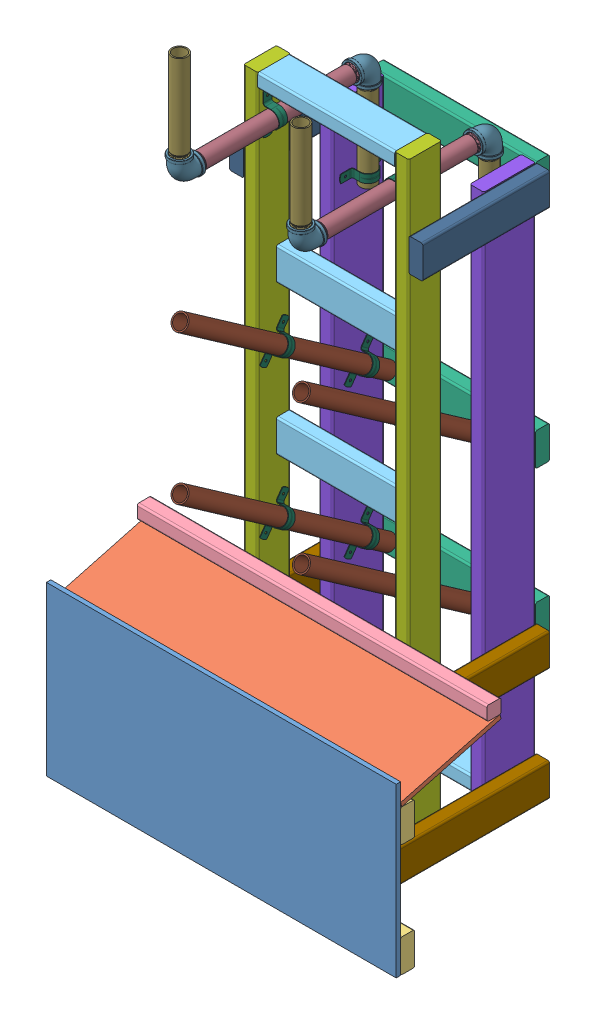
SolidWorks assembly TE-25300, configuration Full Assembly. Lengths in mm.
Overall size (946.66 1825.49 664.9).
50 component instances, 16 part files, 102 mates.
Components (placement in the parent):
- TE Goal Layout-1: TE Goal Layout [Default] at origin size (946.66 1825.49 664.9) (hidden)
- TE-25301-1: TE-25301 [Default] at (0 0 831.7368) size (946.66 454.03 11.91)
- TE-25302-1: TE-25302 [Default] at (0 582.9571 156.2029) x (1 0 0) z (0 0.965926 0.258819) size (946.66 278.4 11.91)
- TE-25303-1: TE-25303 [Default] at (473.3294 0 0) x (0 0 -1) z (1 0 0) size (38.1 88.9 946.66)
- TE-25303-2: TE-25303 [Default] at (473.3294 304.7381 0) x (0 0 -1) z (1 0 0) size (38.1 88.9 946.66)
- TE-25304-1: TE-25304 [Default] at (473.3294 0 0) x (0 0 -1) z (1 0 0) size (38.1 38.1 946.66)
- TE-25305-1: TE-25305 [Default] at (185.3882 0 0) x (0 0 1) z (-1 0 0) size (88.9 38.1 370.78)
- TE-25305-2: TE-25305 [Default] at (185.3882 0 -254) x (0 0 1) z (-1 0 0) size (88.9 38.1 370.78)
- TE-25305-3: TE-25305 [Default] at (185.3882 270.0939 497.0322) x (0 1 0) z (-1 0 0) size (88.9 38.1 370.78)
- TE-25305-4: TE-25305 [Default] at (185.3882 673.1937 497.0322) x (0 1 0) z (-1 0 0) size (88.9 38.1 370.78)
- TE-25305-5: TE-25305 [Default] at (185.3882 1612.9 0) x (0 0 1) z (-1 0 0) size (88.9 38.1 370.78)
- TE-25306-1: TE-25306 [Default] at (223.4882 0 0) x (0 0 -1) z (1 0 0) size (38.1 88.9 446.98)
- TE-25306-2: TE-25306 [Default] at (223.4882 403.0998 0) x (0 0 -1) z (1 0 0) size (38.1 88.9 446.98)
- TE-25306-3: TE-25306 [Default] at (223.4882 1032.6496 0) x (0 0 -1) z (1 0 0) size (38.1 88.9 446.98)
- TE-25321-1: TE-25321 [Default] at (223.4882 0 0) x (0 0 -1) z (1 0 0) size (88.9 1651 38.1)
- TE-25322-1: TE-25322 [Default] at (223.4882 0 0) x (0 0 -1) z (1 0 0) size (139.7 1473.2 38.1)
- TE-25324-2: TE-25324 [Default] at (261.5883 0 0) x (0 0 -1) z (1 0 0) size (576.8 88.9 38.1)
- TE-25324-3: TE-25324 [Default] at (261.5883 304.7381 0) x (0 0 -1) z (1 0 0) size (576.8 88.9 38.1)
- TE-25323-1: TE-25323 [Default] at (0 0 547.8322) size (38.1 88.9 342.9)
- TE-25312-1: TE-25312 [Default] at (0 625.9586 893.9616) x (1 0 0) z (0 0.573576 0.819152) size (42.16 42.16 686.36)
- TE-25312-2: TE-25312 [Default] at (0 1029.0584 893.9616) x (1 0 0) z (0 0.573576 0.819152) size (42.16 42.16 686.36)
- TE-25313-1: TE-25313 [9157K765] at (164.3062 1698.4878 780.7502) x (0 -1 0) z (0 0 1) size (254.3 44.49 44.03)
- TE-25314-1: TE-25314 [4457K117] at (164.3062 1545.0718 525.7342) size (44.11 43.64 458.81)
- TE-25315-1: TE-25315 [44605K117] at (164.3062 1545.0718 780.7502) x (0 0 1) z (-1 0 0) size (71.9 71.9 54.61)
- TE-25313-2: TE-25313 [9157K765] at (164.3062 1391.6558 270.7182) x (0 1 0) z (-0.546944 0 0.837169) size (254.3 44.49 44.03)
- TE-25315-2: TE-25315 [44605K117] at (164.3062 1545.0718 270.7182) x (0 1 0) z (1 0 0) size (71.9 71.9 54.61)
- TE-25316-1: TE-25316 [9439T23] at (163.9506 1290.0558 270.7182) x (0 0 -1) z (0 1 0) size (111.12 44.78 22.23)
- TE-25316-2: TE-25316 [9439T23] at (163.9506 1545.0718 522.4322) x (0 1 0) z (0 0 1) size (111.12 44.78 22.23)
- TE-25316-3: TE-25316 [9439T23] at (163.9506 839.6426 274.7822) x (0 0.819152 -0.573576) z (0 0.573576 0.819152) size (111.12 44.78 22.23)
- TE-25316-4: TE-25316 [9439T23] at (163.9506 999.7101 503.3822) x (0 0.819152 -0.573576) z (0 0.573576 0.819152) size (111.12 44.78 22.23)
- TE-25316-5: TE-25316 [9439T23] at (163.9506 436.5429 274.7822) x (0 0.819152 -0.573576) z (0 0.573576 0.819152) size (111.12 44.78 22.23)
- TE-25316-6: TE-25316 [9439T23] at (163.9506 596.6103 503.3822) x (0 0.819152 -0.573576) z (0 0.573576 0.819152) size (111.12 44.78 22.23)
- TE-25321-2: TE-25321 [Default] at (-185.3882 0 0) x (0 0 -1) z (1 0 0) size (88.9 1651 38.1)
- TE-25314-2: TE-25314 [4457K117] at (-164.3062 1544.7026 525.7342) x (-1 0 0) z (0 0 1) size (44.11 43.64 458.81)
- TE-25324-4: TE-25324 [Default] at (-223.4882 0 0) x (0 0 -1) z (1 0 0) size (576.8 88.9 38.1)
- TE-25323-2: TE-25323 [Default] at (0 0 204.9322) x (-1 0 0) z (0 0 -1) size (38.1 88.9 342.9)
- TE-25322-2: TE-25322 [Default] at (-185.3882 0 0) x (0 0 -1) z (1 0 0) size (139.7 1473.2 38.1)
- TE-25312-3: TE-25312 [Default] at (0 635.3809 331.7318) x (-1 0 0) z (0 -0.573576 -0.819152) size (42.16 42.16 686.36)
- TE-25313-3: TE-25313 [9157K765] at (-164.0591 1698.4878 780.7502) x (0 -1 0) z (0 0 1) size (254.3 44.49 44.03)
- TE-25324-5: TE-25324 [Default] at (-223.4882 304.7381 0) x (0 0 -1) z (1 0 0) size (576.8 88.9 38.1)
- TE-25312-4: TE-25312 [Default] at (0 232.2811 331.7318) x (-1 0 0) z (0 -0.573576 -0.819152) size (42.16 42.16 686.36)
- TE-25316-7: TE-25316 [9439T23] at (-163.9506 999.7101 503.3822) x (0 0.819152 -0.573576) z (0 -0.573576 -0.819152) size (111.12 44.78 22.23)
- TE-25316-8: TE-25316 [9439T23] at (-163.9506 839.6426 274.7822) x (0 0.819152 -0.573576) z (0 -0.573576 -0.819152) size (111.12 44.78 22.23)
- TE-25316-9: TE-25316 [9439T23] at (-163.9506 436.5429 274.7822) x (0 0.819152 -0.573576) z (0 -0.573576 -0.819152) size (111.12 44.78 22.23)
- TE-25316-10: TE-25316 [9439T23] at (-163.9506 1545.0718 522.4322) x (0 1 0) z (0 0 -1) size (111.12 44.78 22.23)
- TE-25315-3: TE-25315 [44605K117] at (-164.3062 1545.0718 270.7182) x (0 1 0) z (1 0 0) size (71.9 71.9 54.61)
- TE-25316-11: TE-25316 [9439T23] at (-163.9506 1290.0558 270.7182) x (0 0 1) z (0 1 0) size (111.12 44.78 22.23)
- TE-25315-4: TE-25315 [44605K117] at (-164.3062 1545.0718 780.7502) x (0 0 1) z (-1 0 0) size (71.9 71.9 54.61)
- TE-25313-4: TE-25313 [9157K765] at (-164.4262 1391.6558 270.5346) x (0 1 0) z (-0.546944 0 -0.837169) size (254.3 44.49 44.03)
- TE-25316-12: TE-25316 [9439T23] at (-163.9506 596.6103 503.3822) x (0 0.819152 -0.573576) z (0 -0.573576 -0.819152) size (111.12 44.78 22.23)
Mates (geometry in assembly coordinates):
- InPlace1: in place: plane of TE Goal Layout-1 through (0 0 831.7368) normal (0 0 1); plane of TE-25301-1 through (0 0 831.7368) normal (0 0 1); moOrthogonalPlaneRef_w of TE Goal Layout-1 through (0 0 831.7368) normal (0 0 1); plane of TE-25301-1 through (0 0 831.7368) normal (0 1 0); plane of TE Goal Layout-1 through (0 0 831.7368) normal (0 0 1); plane of TE-25301-1 through (0 0 831.7368) normal (1 0 0); plane of TE Goal Layout-1 through (0 0 831.7368) normal (0 0 1); unknown of TE-25301-1
- Coincident1: coincident aligned: plane of ?; plane of ?
- Coincident2: coincident aligned: moOrthogonalPlaneRef_w of TE Goal Layout-1 through (0 0 831.7368) normal (0 1 0); plane of Part3^TE-25300-1 through (0 0 831.7368) normal (0 1 0)
- Coincident3: coincident anti-aligned: moOrthogonalPlaneRef_w of TE Goal Layout-1 through (0 0 831.7368) normal (-1 0 0); plane of Part3^TE-25300-1 through (0 0 831.7368) normal (1 0 0)
- InPlace2: in place: plane of TE Goal Layout-1 through (-817.3021 582.9571 156.2029) normal (0 0.965926 0.258819); plane of TE-25302-1 through (0 582.9571 156.2029) normal (0 0.965926 0.258819); plane of TE Goal Layout-1 through (-817.3021 582.9571 156.2029) normal (0 0.965926 0.258819); plane of TE-25302-1 through (0 582.9571 156.2029) normal (0 0.258819 -0.965926); plane of TE Goal Layout-1 through (-817.3021 582.9571 156.2029) normal (0 0.965926 0.258819); plane of TE-25302-1 through (0 582.9571 156.2029) normal (1 0 0); plane of TE Goal Layout-1 through (-817.3021 582.9571 156.2029) normal (0 0.965926 0.258819); unknown of TE-25302-1
- Coincident4: coincident aligned: plane of ?; plane of ?
- Coincident5: coincident aligned: moOrthogonalPlaneRef_w of TE Goal Layout-1 through (0 582.9571 156.2029) normal (0 0.258819 -0.965926); plane of Part4^TE-25300-1 through (0 582.9571 156.2029) normal (0 0.258819 -0.965926)
- Coincident6: coincident anti-aligned: moOrthogonalPlaneRef_w of TE Goal Layout-1 through (0 582.9571 156.2029) normal (-1 0 0); plane of Part4^TE-25300-1 through (0 582.9571 156.2029) normal (1 0 0)
- InPlace3: in place: plane of TE Goal Layout-1 through (473.3294 0 819.8306) normal (1 0 0); plane of ? through (473.3294 0 0) normal (1 0 0); plane of TE Goal Layout-1 through (473.3294 0 819.8306) normal (1 0 0); plane of ? through (473.3294 0 0) normal (0 1 0); plane of TE Goal Layout-1 through (473.3294 0 819.8306) normal (1 0 0); plane of ? through (473.3294 0 0) normal (0 0 -1); plane of TE Goal Layout-1 through (473.3294 0 819.8306) normal (1 0 0); unknown of ?
- Coincident7: coincident aligned: plane of ?; plane of ?
- Coincident8: coincident aligned: moOrthogonalPlaneRef_w of TE Goal Layout-1 through (473.3294 0 0) normal (0 1 0); plane of Part5^TE-25300-1 through (473.3294 0 0) normal (0 1 0)
- Coincident9: coincident anti-aligned: moOrthogonalPlaneRef_w of TE Goal Layout-1 through (473.3294 0 0) normal (0 0 1); plane of Part5^TE-25300-1 through (473.3294 0 0) normal (0 0 -1)
- InPlace4: in place: plane of TE Goal Layout-1 through (473.3294 0 819.8306) normal (1 0 0); plane of ? through (473.3294 0 0) normal (1 0 0); plane of TE Goal Layout-1 through (473.3294 0 819.8306) normal (1 0 0); plane of ? through (473.3294 0 0) normal (0 1 0); plane of TE Goal Layout-1 through (473.3294 0 819.8306) normal (1 0 0); plane of ? through (473.3294 0 0) normal (0 0 -1); plane of TE Goal Layout-1 through (473.3294 0 819.8306) normal (1 0 0); unknown of ?
- Coincident10: coincident aligned: plane of ?; plane of ?
- Coincident11: coincident aligned: moOrthogonalPlaneRef_w of TE Goal Layout-1 through (473.3294 0 0) normal (0 1 0); plane of Part6^TE-25300-1 through (473.3294 0 0) normal (0 1 0)
- Coincident12: coincident anti-aligned: moOrthogonalPlaneRef_w of TE Goal Layout-1 through (473.3294 0 0) normal (0 0 1); plane of Part6^TE-25300-1 through (473.3294 0 0) normal (0 0 -1)
- InPlace5: in place: plane of TE Goal Layout-1 through (185.3882 1612.9 458.9322) normal (-1 0 0); plane of TE-25305-1 through (185.3882 0 0) normal (-1 0 0); plane of TE Goal Layout-1 through (185.3882 1612.9 458.9322) normal (-1 0 0); plane of TE-25305-1 through (185.3882 0 0) normal (0 1 0); plane of TE Goal Layout-1 through (185.3882 1612.9 458.9322) normal (-1 0 0); plane of TE-25305-1 through (185.3882 0 0) normal (0 0 1); plane of TE Goal Layout-1 through (185.3882 1612.9 458.9322) normal (-1 0 0); unknown of TE-25305-1
- Coincident13: coincident aligned: plane of ?; plane of ?
- Coincident14: coincident aligned: moOrthogonalPlaneRef_w of TE Goal Layout-1 through (185.3882 0 0) normal (0 1 0); plane of Part7^TE-25300-1 through (185.3882 0 0) normal (0 1 0)
- Coincident15: coincident anti-aligned: moOrthogonalPlaneRef_w of TE Goal Layout-1 through (185.3882 0 0) normal (0 0 -1); plane of Part7^TE-25300-1 through (185.3882 0 0) normal (0 0 1)
- InPlace6: in place: plane of TE Goal Layout-1 through (223.4882 1473.2 204.9322) normal (1 0 0); plane of ? through (223.4882 0 0) normal (1 0 0); plane of TE Goal Layout-1 through (223.4882 1473.2 204.9322) normal (1 0 0); plane of ? through (223.4882 0 0) normal (0 1 0); plane of TE Goal Layout-1 through (223.4882 1473.2 204.9322) normal (1 0 0); plane of ? through (223.4882 0 0) normal (0 0 -1); plane of TE Goal Layout-1 through (223.4882 1473.2 204.9322) normal (1 0 0); unknown of ?
- Coincident16: coincident aligned: plane of ?; plane of ?
- Coincident17: coincident aligned: moOrthogonalPlaneRef_w of TE Goal Layout-1 through (223.4882 0 0) normal (0 1 0); plane of Part8^TE-25300-1 through (223.4882 0 0) normal (0 1 0)
- Coincident18: coincident anti-aligned: moOrthogonalPlaneRef_w of TE Goal Layout-1 through (223.4882 0 0) normal (0 0 1); plane of Part8^TE-25300-1 through (223.4882 0 0) normal (0 0 -1)
- InPlace7: in place: plane of TE Goal Layout-1 through (185.3882 1612.9 458.9322) normal (-1 0 0); plane of TE-25305-1 through (185.3882 0 0) normal (-1 0 0); plane of TE Goal Layout-1 through (185.3882 1612.9 458.9322) normal (-1 0 0); plane of TE-25305-1 through (185.3882 0 0) normal (0 1 0); plane of TE Goal Layout-1 through (185.3882 1612.9 458.9322) normal (-1 0 0); plane of TE-25305-1 through (185.3882 0 0) normal (0 0 1); plane of TE Goal Layout-1 through (185.3882 1612.9 458.9322) normal (-1 0 0); unknown of TE-25305-1
- Coincident19: coincident aligned: plane of ?; plane of ?
- Coincident20: coincident aligned: moOrthogonalPlaneRef_w of TE Goal Layout-1 through (185.3882 0 0) normal (0 1 0); plane of Part9^TE-25300-1 through (185.3882 0 0) normal (0 1 0)
- Coincident21: coincident anti-aligned: moOrthogonalPlaneRef_w of TE Goal Layout-1 through (185.3882 0 0) normal (0 0 -1); plane of Part9^TE-25300-1 through (185.3882 0 0) normal (0 0 1)
- InPlace8: in place: plane of TE Goal Layout-1 through (223.4882 0 458.9322) normal (1 0 0); plane of ? through (223.4882 0 0) normal (1 0 0); plane of TE Goal Layout-1 through (223.4882 0 458.9322) normal (1 0 0); plane of ? through (223.4882 0 0) normal (0 1 0); plane of TE Goal Layout-1 through (223.4882 0 458.9322) normal (1 0 0); plane of ? through (223.4882 0 0) normal (0 0 -1); plane of TE Goal Layout-1 through (223.4882 0 458.9322) normal (1 0 0); unknown of ?
- Coincident22: coincident aligned: plane of ?; plane of ?
- Coincident23: coincident aligned: moOrthogonalPlaneRef_w of TE Goal Layout-1 through (223.4882 0 0) normal (0 1 0); plane of Part10^TE-25300-1 through (223.4882 0 0) normal (0 1 0)
- Coincident24: coincident anti-aligned: moOrthogonalPlaneRef_w of TE Goal Layout-1 through (223.4882 0 0) normal (0 0 1); plane of Part10^TE-25300-1 through (223.4882 0 0) normal (0 0 -1)
- InPlace9: in place: plane of TE Goal Layout-1 through (223.4882 1473.2 204.9322) normal (1 0 0); plane of ? through (223.4882 0 0) normal (1 0 0); plane of TE Goal Layout-1 through (223.4882 1473.2 204.9322) normal (1 0 0); plane of ? through (223.4882 0 0) normal (0 1 0); plane of TE Goal Layout-1 through (223.4882 1473.2 204.9322) normal (1 0 0); plane of ? through (223.4882 0 0) normal (0 0 -1); plane of TE Goal Layout-1 through (223.4882 1473.2 204.9322) normal (1 0 0); unknown of ?
- Coincident25: coincident aligned: plane of ?; plane of ?
- Coincident26: coincident aligned: moOrthogonalPlaneRef_w of TE Goal Layout-1 through (223.4882 0 0) normal (0 1 0); plane of Part11^TE-25300-1 through (223.4882 0 0) normal (0 1 0)
- Coincident27: coincident anti-aligned: moOrthogonalPlaneRef_w of TE Goal Layout-1 through (223.4882 0 0) normal (0 0 1); plane of Part11^TE-25300-1 through (223.4882 0 0) normal (0 0 -1)
- InPlace10: in place: plane of TE Goal Layout-1 through (261.5883 88.9 0) normal (1 0 0); plane of TE-25324-2 through (261.5883 0 0) normal (1 0 0); plane of TE Goal Layout-1 through (261.5883 88.9 0) normal (1 0 0); plane of TE-25324-2 through (261.5883 0 0) normal (0 1 0); plane of TE Goal Layout-1 through (261.5883 88.9 0) normal (1 0 0); plane of TE-25324-2 through (261.5883 0 0) normal (0 0 -1); plane of TE Goal Layout-1 through (261.5883 88.9 0) normal (1 0 0); unknown of TE-25324-2
- Coincident28: coincident aligned: plane of ?; plane of ?
- Coincident29: coincident aligned: moOrthogonalPlaneRef_w of TE Goal Layout-1 through (261.5883 0 0) normal (0 1 0); plane of Part12^TE-25300-1 through (261.5883 0 0) normal (0 1 0)
- Coincident30: coincident anti-aligned: moOrthogonalPlaneRef_w of TE Goal Layout-1 through (261.5883 0 0) normal (0 0 1); plane of Part12^TE-25300-1 through (261.5883 0 0) normal (0 0 -1)
- InPlace11: in place: plane of TE Goal Layout-1 through (0 0 547.8322) normal (0 0 1); plane of TE-25323-1 through (0 0 547.8322) normal (0 0 1); plane of TE Goal Layout-1 through (0 0 547.8322) normal (0 0 1); plane of TE-25323-1 through (0 0 547.8322) normal (0 1 0); plane of TE Goal Layout-1 through (0 0 547.8322) normal (0 0 1); plane of TE-25323-1 through (0 0 547.8322) normal (1 0 0); plane of TE Goal Layout-1 through (0 0 547.8322) normal (0 0 1); unknown of TE-25323-1
- Coincident31: coincident aligned: plane of ?; plane of ?
- Coincident32: coincident aligned: moOrthogonalPlaneRef_w of TE Goal Layout-1 through (0 0 547.8322) normal (0 1 0); plane of Part13^TE-25300-1 through (0 0 547.8322) normal (0 1 0)
- Coincident33: coincident anti-aligned: moOrthogonalPlaneRef_w of TE Goal Layout-1 through (0 0 547.8322) normal (-1 0 0); plane of Part13^TE-25300-1 through (0 0 547.8322) normal (1 0 0)
- Coincident34: coincident anti-aligned: plane of TE-25301-1 through (0 0 819.8306) normal (0 0 -1); plane of TE-25303-2 through (-570.0497 393.6381 819.8306) normal (0 0 1)
- Coincident35: coincident aligned: plane of TE-25301-1 through (473.3294 454.025 -230.0749) normal (1 0 0); plane of TE-25303-2 through (473.3294 304.7381 0) normal (1 0 0)
- Coincident36: coincident anti-aligned: plane of TE-25324-3 through (-360.1209 393.6381 781.7306) normal (0 0 1); plane of TE-25303-2 through (-570.0497 393.6381 781.7306) normal (0 0 -1)
- Coincident37: coincident aligned: plane of TE-25324-3 through (-360.1209 393.6381 781.7306) normal (0 1 0); plane of TE-25303-2 through (-570.0497 393.6381 781.7306) normal (0 1 0)
- Coincident38: coincident anti-aligned: plane of TE-25322-1 through (223.4882 0 0) normal (1 0 0); plane of TE-25324-3 through (223.4882 1777.9381 204.9322) normal (-1 0 0)
- Coincident39: coincident aligned: plane of TE Goal Layout-1 through (-817.3021 393.6381 0) normal (0 1 0); plane of TE-25303-2 through (-570.0497 393.6381 781.7306) normal (0 1 0)
- InPlace12: in place: plane of TE Goal Layout-1 through (164.3062 789.7779 779.2541) normal (0 0.573576 0.819152); plane of TE-25312-1 through (0 625.9586 893.9616) normal (0 0.573576 0.819152); plane of TE Goal Layout-1 through (164.3062 789.7779 779.2541) normal (0 0.573576 0.819152); plane of TE-25312-1 through (0 625.9586 893.9616) normal (0 0.819152 -0.573576); plane of TE Goal Layout-1 through (164.3062 789.7779 779.2541) normal (0 0.573576 0.819152); plane of TE-25312-1 through (0 625.9586 893.9616) normal (1 0 0); plane of TE Goal Layout-1 through (164.3062 789.7779 779.2541) normal (0 0.573576 0.819152); unknown of TE-25312-1
- Coincident40: coincident aligned: plane of ?; plane of ?
- Coincident41: coincident aligned: moOrthogonalPlaneRef_w of TE Goal Layout-1 through (0 625.9586 893.9616) normal (0 0.819152 -0.573576); plane of Part14^TE-25300-1 through (0 625.9586 893.9616) normal (0 0.819152 -0.573576)
- Coincident42: coincident anti-aligned: moOrthogonalPlaneRef_w of TE Goal Layout-1 through (0 625.9586 893.9616) normal (-1 0 0); plane of Part14^TE-25300-1 through (0 625.9586 893.9616) normal (1 0 0)
- Concentric1: concentric aligned: cylinder of TE Goal Layout-1 through (164.3062 1192.8777 779.2541) axis (0 0.573576 0.819152) radius 21.082; cylinder of TE-25312-2 through (164.3062 764.9984 168.1792) axis (0 0.573576 0.819152) radius 21.082
- Coincident43: coincident aligned: plane of TE Goal Layout-1 through (164.3062 1192.8777 779.2541) normal (0 0.573576 0.819152); plane of TE-25312-2 through (164.3062 1192.8777 779.2541) normal (0 0.573576 0.819152)
- Concentric2: concentric aligned: cylinder of TE Goal Layout-1 through (164.3062 1545.0718 754.3342) axis (0 0 1) radius 21.082; cylinder of TE-25314-1 through (164.3062 1545.0718 754.3342) axis (0 0 1) radius 21.082
- Width1: width anti-aligned: plane of TE-25314-1 through (164.3062 1563.5619 754.3342) normal (0 0 1); plane of TE-25314-1 through (164.3062 1562.5978 297.1342) normal (0 0 -1); plane of TE Goal Layout-1 through (191.6113 1589.5218 736.3002) normal (0 0 -1); plane of TE Goal Layout-1 through (191.6113 1572.3768 315.1682) normal (0 0 1)
- Concentric3: concentric anti-aligned: cylinder of TE Goal Layout-1 through (164.3062 1825.4878 780.7502) axis (0 1 0) radius 21.082; cylinder of TE-25313-1 through (164.3062 1825.4878 780.7502) axis (0 -1 0) radius 21.082
- Coincident44: coincident aligned: plane of TE Goal Layout-1 through (164.3062 1825.4878 780.7502) normal (0 1 0); plane of TE-25313-1 through (164.3062 1825.4878 780.7502) normal (0 1 0)
- Concentric4: concentric aligned: cylinder of TE Goal Layout-1 through (164.3062 1518.6558 270.7182) axis (0 1 0) radius 21.082; cylinder of TE-25313-2 through (164.3062 1264.6558 270.7182) axis (0 1 0) radius 21.082
- Coincident45: coincident aligned: plane of TE Goal Layout-1 through (164.3062 1264.6558 270.7182) normal (0 -1 0); plane of TE-25313-2 through (164.3062 1264.6558 270.7182) normal (0 -1 0)
- Concentric5: concentric aligned: cylinder of TE-25313-1 through (164.3062 1825.4878 780.7502) axis (0 -1 0) radius 21.082; cylinder of TE-25315-1 through (164.3062 1545.0718 780.7502) axis (0 -1 0) radius 27.305
- Concentric6: concentric aligned: cylinder of TE-25314-1 through (164.3062 1545.0718 754.3342) axis (0 0 1) radius 21.082; cylinder of TE-25315-1 through (164.3062 1545.0718 780.7502) axis (0 0 1) radius 27.305
- Concentric7: concentric anti-aligned: cylinder of TE-25314-1 through (164.3062 1545.0718 754.3342) axis (0 0 1) radius 21.082; cylinder of TE-25315-2 through (164.3062 1545.0718 270.7182) axis (0 0 -1) radius 27.305
- Concentric8: concentric aligned: cylinder of TE-25313-2 through (164.3062 1264.6558 270.7182) axis (0 1 0) radius 21.082; cylinder of TE-25315-2 through (164.3062 1545.0718 270.7182) axis (0 1 0) radius 27.305
- Coincident46: coincident: line of TE-25313-2 through (164.3062 1264.6558 270.7182) axis (0 1 0); plane of TE-25316-1 through (163.9506 1290.0558 270.7182) normal (0 0 -1)
- Coincident47: coincident anti-aligned: plane of TE-25322-1 through (185.3882 1473.2 204.9322) normal (-1 0 0); plane of TE-25316-1 through (185.3882 1301.1683 215.1557) normal (1 0 0)
- Coincident48: coincident: line of TE-25314-1 through (164.3062 1545.0718 322.7501) axis (0 0 1); plane of TE-25316-2 through (163.9506 1545.0718 522.4322) normal (0 1 0)
- Coincident49: coincident anti-aligned: plane of TE-25321-1 through (185.3882 1612.9 458.9322) normal (-1 0 0); plane of TE-25316-2 through (185.3882 1600.6343 533.5447) normal (1 0 0)
- Distance1: distance = 25.4 mm: plane of TE-25321-1 through (-1468.0035 1651 547.8322) normal (0 0 1); line of TE-25316-2 through (185.3882 1586.3468 522.4322) axis (-1 0 0)
- Distance2: distance = 25.4 mm: plane of TE-25313-2 through (164.3062 1264.6558 270.7182) normal (0 -1 0); line of TE-25316-1 through (185.3882 1290.0558 311.9932) axis (-1 0 0)
- Coincident52: coincident: line of TE-25312-2 through (164.3062 799.2001 217.0243) axis (0 0.573576 0.819152); plane of TE-25316-3 through (163.9506 839.6426 274.7822) normal (0 0.819152 -0.573576)
- Coincident53: coincident: line of TE-25312-2 through (164.3062 799.2001 217.0243) axis (0 0.573576 0.819152); plane of TE-25316-4 through (163.9506 999.7101 503.3822) normal (0 0.819152 -0.573576)
- Coincident54: coincident: line of TE-25312-1 through (164.3062 396.1004 217.0243) axis (0 0.573576 0.819152); plane of TE-25316-5 through (163.9506 436.5429 274.7822) normal (0 0.819152 -0.573576)
- Coincident55: coincident: line of TE-25312-1 through (164.3062 396.1004 217.0243) axis (0 0.573576 0.819152); plane of TE-25316-6 through (163.9506 596.6103 503.3822) normal (0 0.819152 -0.573576)
- Coincident56: coincident anti-aligned: plane of TE-25322-1 through (185.3882 1473.2 204.9322) normal (-1 0 0); plane of TE-25316-3 through (185.3882 891.5306 252.0157) normal (1 0 0)
- Coincident57: coincident anti-aligned: plane of TE-25321-1 through (185.3882 1612.9 458.9322) normal (-1 0 0); plane of TE-25316-4 through (185.3882 1051.5981 480.6157) normal (1 0 0)
- Coincident58: coincident anti-aligned: plane of TE-25322-1 through (185.3882 1473.2 204.9322) normal (-1 0 0); plane of TE-25316-5 through (185.3882 488.4309 252.0157) normal (1 0 0)
- Coincident59: coincident anti-aligned: plane of TE-25321-1 through (185.3882 1612.9 458.9322) normal (-1 0 0); plane of TE-25316-6 through (185.3882 648.4983 480.6157) normal (1 0 0)
- Coincident60: coincident: plane of TE-25322-1 through (223.4882 0 274.7822) normal (0 0 -1); line of TE-25316-3 through (138.3697 839.6426 274.7822) axis (1 0 0)
- Coincident61: coincident: plane of TE-25321-1 through (223.4882 0 503.3822) normal (0 0 -1); line of TE-25316-4 through (138.3697 999.7101 503.3822) axis (1 0 0)
- Coincident62: coincident: plane of TE-25322-1 through (223.4882 0 274.7822) normal (0 0 -1); line of TE-25316-5 through (138.3697 436.5429 274.7822) axis (1 0 0)
- Coincident63: coincident: plane of TE-25321-1 through (223.4882 0 503.3822) normal (0 0 -1); line of TE-25316-6 through (138.3697 596.6103 503.3822) axis (1 0 0)
- Coincident78: coincident anti-aligned: plane of TE-25322-1 through (185.3882 1473.2 204.9322) normal (-1 0 0); plane of TE-25305-2 through (185.3882 0 -254) normal (1 0 0)
- Coincident79: coincident aligned: plane of TE-25322-1 through (-1294.4206 0 344.6322) normal (0 -1 0); plane of TE-25305-2 through (-282.1086 0 204.9322) normal (0 -1 0)
- Coincident80: coincident aligned: plane of TE-25322-1 through (-1294.4206 1473.2 204.9322) normal (0 0 -1); plane of TE-25305-2 through (-282.1086 38.1 204.9322) normal (0 0 -1)
- Coincident81: coincident anti-aligned: plane of TE-25322-1 through (-1294.4206 1473.2 204.9322) normal (0 0 -1); plane of TE-25306-2 through (-320.2086 843.6501 204.9322) normal (0 0 1)
- Coincident82: coincident aligned: plane of TE-25322-1 through (223.4882 0 0) normal (1 0 0); plane of TE-25306-2 through (223.4882 403.0998 0) normal (1 0 0)
- Coincident83: coincident anti-aligned: plane of TE-25322-1 through (-1294.4206 1473.2 204.9322) normal (0 0 -1); plane of TE-25306-3 through (-320.2086 1473.2 204.9322) normal (0 0 1)
- Coincident84: coincident aligned: plane of TE-25322-1 through (223.4882 0 0) normal (1 0 0); plane of TE-25306-3 through (223.4882 1032.6496 0) normal (1 0 0)
- Coincident85: coincident anti-aligned: plane of TE-25321-1 through (185.3882 1612.9 458.9322) normal (-1 0 0); plane of TE-25305-5 through (185.3882 1612.9 0) normal (1 0 0)
- Coincident86: coincident aligned: plane of TE-25321-1 through (-1468.0035 1651 458.9322) normal (0 0 -1); plane of TE-25305-5 through (-282.1086 1651 458.9322) normal (0 0 -1)
- Coincident87: coincident aligned: plane of TE-25321-1 through (-1468.0035 1651 547.8322) normal (0 1 0); plane of TE-25305-5 through (-282.1086 1651 458.9322) normal (0 1 0)
- Coincident88: coincident anti-aligned: plane of TE-25321-1 through (185.3882 1612.9 458.9322) normal (-1 0 0); plane of TE-25305-3 through (185.3882 270.0939 497.0322) normal (1 0 0)
- Coincident89: coincident anti-aligned: plane of TE-25321-1 through (185.3882 1612.9 458.9322) normal (-1 0 0); plane of TE-25305-4 through (185.3882 673.1937 497.0322) normal (1 0 0)
- Coincident90: coincident aligned: plane of TE-25321-1 through (-1468.0035 1651 458.9322) normal (0 0 -1); plane of TE-25305-3 through (-282.1086 729.0261 458.9322) normal (0 0 -1)
- Coincident91: coincident aligned: plane of TE-25321-1 through (-1468.0035 1651 458.9322) normal (0 0 -1); plane of TE-25305-4 through (-282.1086 1132.1259 458.9322) normal (0 0 -1)
- Coincident92: coincident aligned: plane of TE-25322-1 through (-1294.4206 1473.2 344.6322) normal (0 1 0); plane of TE-25306-3 through (-320.2086 1473.2 204.9322) normal (0 1 0)
- Coincident93: coincident aligned: plane of TE Goal Layout-1 through (223.4882 843.6501 204.9322) normal (0 1 0); plane of TE-25306-2 through (-320.2086 843.6501 204.9322) normal (0 1 0)
- Coincident94: coincident aligned: plane of TE Goal Layout-1 through (282.1086 817.9261 458.9322) normal (0 1 0); plane of TE-25305-3 through (-282.1086 817.9261 458.9322) normal (0 1 0)
- Coincident95: coincident aligned: plane of TE Goal Layout-1 through (282.1086 1221.0259 458.9322) normal (0 1 0); plane of TE-25305-4 through (-282.1086 1221.0259 458.9322) normal (0 1 0)
